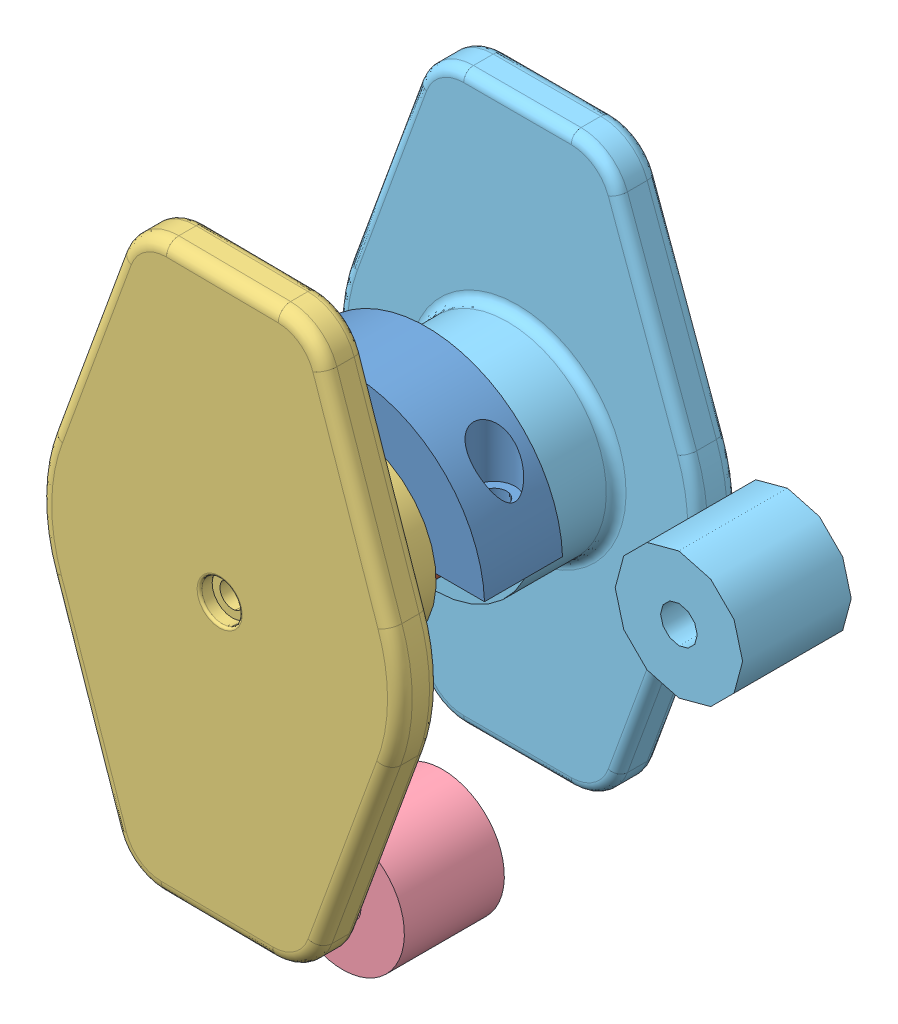
SolidWorks assembly collar_des2, configuration Default. Lengths in mm.
Overall size (74.12 121.35 68.94).
8 component instances, 7 part files, 13 mates.
Components (placement in the parent):
- bottom_collar2-1: bottom_collar2 [Default] at (45.7671 27.9762 95.3479) size (105 89.54 44) (hidden)
- top_collar2-1: top_collar2 [Default] at (45.7867 27.7432 95.3479) size (55.04 26.54 15.8)
- LCFD-1: LCFD [Default] at (45.7671 89.9762 87.1979) x (0 -1 0) z (0 0 1) size (32.7 25.4 16.3)
- GFAttachmentOval-1: GFAttachmentOval [Default] at (45.7671 89.9762 94.7529) x (0 0 -1) z (-0.999987 -0.00504 0) size (25.74 115 73) (hidden)
- LC_attachmentV2-1: LC_attachmentV2 [Default] at (45.7671 89.9762 94.9529) x (0 0 -1) z (1 0 0) size (18 25.8 76.25) (hidden)
- GFAttachmentOval-2: GFAttachmentOval [Default] at (45.7671 89.9762 95.3929) x (0 0 1) z (-0.999953 0.00974 0) size (25.74 115 73)
- LC_attachmentV3-1: LC_attachmentV3 [Default] at (45.7671 89.9762 129.5029) x (0 0 -1) z (0.335075 -0.942191 0) size (20.25 25 75.45)
- GFhexAttachment-1: GFhexAttachment [Default] at (45.7671 89.9762 94.9529) x (0 0 -1) z (1 0 0) size (26.25 115 99.85)
Mates (geometry in assembly coordinates):
- Concentric1: concentric anti-aligned: cylinder of bottom_collar2-1 through (45.7671 88.9762 95.3479) axis (0 -1 0) radius 3.325; cylinder of LCFD-1 through (45.7671 69.9762 95.3479) axis (0 1 0) radius 3.175
- Coincident1: coincident aligned: plane of bottom_collar2-1 through (45.7671 89.9762 87.3479) normal (0 0 -1); plane of top_collar2-1 through (45.7867 27.7432 87.3479) normal (0 0 -1)
- Coincident2: coincident: plane of bottom_collar2-1 through (18.2685 40.4762 103.3479) normal (-1 0 0); line of top_collar2-1 through (18.2685 90.7432 103.1479) axis (0 0 -1)
- Concentric2: concentric aligned: cylinder of bottom_collar2-1 through (45.7671 89.9762 103.3479) axis (0 0 -1) radius 13.25; cylinder of LCFD-1 through (45.7671 89.9762 100.4979) axis (0 0 -1) radius 12.7
- Distance1: distance = 0.5 mm anti-aligned: plane of LC_attachmentV2-1 through (45.7671 89.9762 86.6979) normal (0 0 1); plane of LCFD-1 through (45.7671 89.9762 87.1979) normal (0 0 -1)
- Concentric3: concentric anti-aligned: cylinder of LCFD-1 through (45.7671 89.9762 100.4979) axis (0 0 -1) radius 12.7; cylinder of LC_attachmentV2-1 through (45.7671 89.9762 86.6979) axis (0 0 1) radius 12.9
- Concentric4: concentric aligned: cylinder of GFAttachmentOval-1 through (45.7671 89.9762 68.6979) axis (0 0 1) radius 13.125; cylinder of LC_attachmentV2-1 through (45.7671 89.9762 86.6979) axis (0 0 1) radius 12.9
- Concentric5: concentric anti-aligned: cylinder of LCFD-1 through (45.7671 89.9762 100.4979) axis (0 0 -1) radius 12.7; cylinder of LC_attachmentV3-1 through (45.7671 89.9762 121.2479) axis (0 0 1) radius 12.5
- Distance3: distance = 0.5 mm anti-aligned: plane of LC_attachmentV3-1 through (45.7671 89.9762 100.9979) normal (0 0 -1); plane of LCFD-1 through (45.7671 89.9762 100.4979) normal (0 0 1)
- Concentric6: concentric anti-aligned: cylinder of GFAttachmentOval-2 through (45.7671 89.9762 121.4479) axis (0 0 -1) radius 13.125; cylinder of LC_attachmentV3-1 through (45.7671 89.9762 121.2479) axis (0 0 1) radius 12.5
- Distance4: distance = 0.5 mm anti-aligned: plane of GFhexAttachment-1 through (45.7671 89.9762 86.6979) normal (0 0 1); plane of LCFD-1 through (45.7671 89.9762 87.1979) normal (0 0 -1)
- Concentric7: concentric aligned: cylinder of LCFD-1 through (45.7671 89.9762 100.4979) axis (0 0 -1) radius 12.7; cylinder of GFhexAttachment-1 through (45.7671 89.9762 85.4479) axis (0 0 -1) radius 20
- Coincident3: coincident anti-aligned: plane of GFAttachmentOval-2 through (45.7671 89.9762 121.2479) normal (0 0 -1); plane of LC_attachmentV3-1 through (45.7671 89.9762 121.2479) normal (0 0 1)
